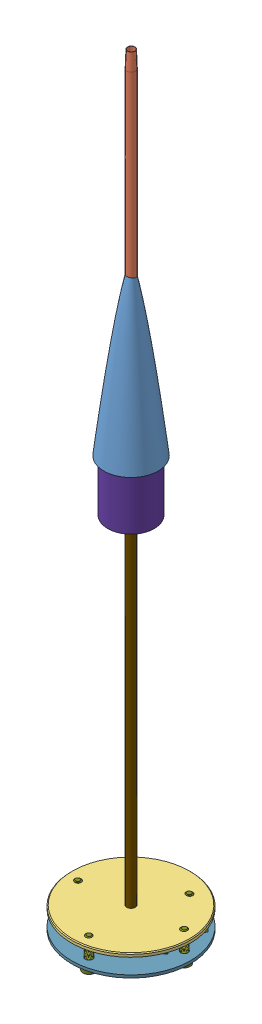
SolidWorks assembly NoseconeAsm, configuration Default. Lengths in mm.
Overall size (98.34 454.25 98.34).
84 component instances, 19 part files, 9 mates.
Components (placement in the parent):
- noseCone-1: noseCone [Default] at (226.7218 161.1206 645.7586) x (-1 0 0) z (0 0 1) size (120 813.97 120) (hidden)
- NOSECONE_TIP-1: NOSECONE_TIP [Default] at (226.717 961.2789 645.6249) x (0 -1 0) z (0.999354 0 -0.035938) size (105.75 31.88 31.88)
- PTube-1: PTube [Default] at (226.717 843.0906 645.6249) x (0.614963 0 0.788556) z (-0.788556 0 0.614963) size (5.11 225 5.11)
- PCB_retainer_Asm-1: PCB_retainer_Asm [Default] at (226.7218 629.513 645.7586) size (98.34 18.34 98.34)
  - Retaining plate-1: Retaining plate [Default] at origin size (70.03 2 70.03)
  - BansheePCB-1: BansheePCB [Default] at (49.813 -10.6 179.2168) x (-0.785717 0 -0.618586) z (0 1 0) size (70.03 70.03 10.55)
    - PT0.step-1: PT0.step [Default] at origin size (70.03 70.03 10.55)
      - PinHeader_2x05_P1.27mm_Vertical.step-1: PinHeader_2x05_P1.27mm_Vertical.step [Default] at (148.25 -130.23 -0.05) x (1 0 0) z (0 0 -1) size (3.4 6.35 6.3)
        - SOLID.step-1: SOLID.step [Default] at origin size (3.4 6.35 6.3)
      - SOT-23.step-1: SOT-23.step [Default] at (138 -129 1.65) size (2.5 3 1.2)
        - SOLID-0.step-1: SOLID-0.step [Default] at origin size (2.5 3 1.2)
      - SOT-23.step-2: SOT-23.step [Default] at (138 -124 1.65) size (2.5 3 1.2)
        - SOLID-0.step-1: SOLID-0.step [Default] at origin size (2.5 3 1.2)
      - R_0805_2012Metric.step-1: R_0805_2012Metric.step [Default] at (177.975 -120 1.65) size (2 1.2 0.45)
        - SOLID-1.step-1: SOLID-1.step [Default] at origin size (2 1.2 0.45)
      - R_0805_2012Metric.step-2: R_0805_2012Metric.step [Default] at (144 -95.975 1.65) x (0 1 0) z (0 0 1) size (2 1.2 0.45)
        - SOLID-1.step-1: SOLID-1.step [Default] at origin size (2 1.2 0.45)
      - R_0805_2012Metric.step-3: R_0805_2012Metric.step [Default] at (146 -96.025 1.65) x (0 1 0) z (0 0 1) size (2 1.2 0.45)
        - SOLID-1.step-1: SOLID-1.step [Default] at origin size (2 1.2 0.45)
      - JST_PH_S2B-PH-K_1x02_P2.00mm_Horizontal.step-1: JST_PH_S2B-PH-K_1x02_P2.00mm_Horizontal.step [Default] at (146 -140 1.65) x (-1 0 0) z (0 0 1) size (5.9 7.6 8.25)
        - SOLID-2.step-1: SOLID-2.step [Default] at origin size (5.9 7.6 8.25)
      - C_0603_1608Metric.step-1: C_0603_1608Metric.step [Default] at (163.7875 -114 1.65) size (1.6 0.8 0.8)
        - SOLID-3.step-1: SOLID-3.step [Default] at origin size (1.6 0.8 0.8)
      - C_0603_1608Metric.step-2: C_0603_1608Metric.step [Default] at (157 -117.7875 1.65) x (0 -1 0) z (0 0 1) size (1.6 0.8 0.8)
        - SOLID-3.step-1: SOLID-3.step [Default] at origin size (1.6 0.8 0.8)
      - QFN-24-1EP_4x4mm_P0.5mm_EP2.7x2.6mm.step-1: QFN-24-1EP_4x4mm_P0.5mm_EP2.7x2.6mm.step [Default] at (176.05 -112.25 1.65) size (4 4 1.1)
        - SOLID-4.step-1: SOLID-4.step [Default] at origin size (4 4 1.1)
      - Bosch_LGA-8_2x2.5mm_P0.65mm_ClockwisePinNumbering.step-1: Bosch_LGA-8_2x2.5mm_P0.65mm_ClockwisePinNumbering.step [Default] at (150 -110 1.65) size (2.5 2 0.78)
        - SOLID-5.step-1: SOLID-5.step [Default] at origin size (2.5 2 0.78)
      - LQFP-48_7x7mm_P0.5mm.step-1: LQFP-48_7x7mm_P0.5mm.step [Default] at (169 -127 1.65) x (0.707107 -0.707107 0) z (0 0 1) size (9 9 1.5)
        - SOLID-6.step-1: SOLID-6.step [Default] at origin size (9 9 1.5)
      - R_0805_2012Metric.step-4: R_0805_2012Metric.step [Default] at (155 -95.975 1.65) x (0 1 0) z (0 0 1) size (2 1.2 0.45)
        - SOLID-1.step-1: SOLID-1.step [Default] at origin size (2 1.2 0.45)
      - R_0805_2012Metric.step-5: R_0805_2012Metric.step [Default] at (142.975 -121 1.65) size (2 1.2 0.45)
        - SOLID-1.step-1: SOLID-1.step [Default] at origin size (2 1.2 0.45)
      - R_0805_2012Metric.step-6: R_0805_2012Metric.step [Default] at (129 -122 1.65) x (0 1 0) z (0 0 1) size (2 1.2 0.45)
        - SOLID-1.step-1: SOLID-1.step [Default] at origin size (2 1.2 0.45)
      - R_0805_2012Metric.step-7: R_0805_2012Metric.step [Default] at (164 -116.975 1.65) x (0 -1 0) z (0 0 1) size (2 1.2 0.45)
        - SOLID-1.step-1: SOLID-1.step [Default] at origin size (2 1.2 0.45)
      - R_0805_2012Metric.step-8: R_0805_2012Metric.step [Default] at (143 -119 1.65) size (2 1.2 0.45)
        - SOLID-1.step-1: SOLID-1.step [Default] at origin size (2 1.2 0.45)
      - R_0805_2012Metric.step-9: R_0805_2012Metric.step [Default] at (131 -121.975 1.65) x (0 1 0) z (0 0 1) size (2 1.2 0.45)
        - SOLID-1.step-1: SOLID-1.step [Default] at origin size (2 1.2 0.45)
      - LED_0805_2012Metric.step-1: LED_0805_2012Metric.step [Default] at (149.025 -121 -0.05) x (-1 0 0) z (0 0 -1) size (2 1.25 1.1)
        - SOLID-7.step-1: SOLID-7.step [Default] at origin size (2 1.25 1.1)
      - LED_0805_2012Metric.step-2: LED_0805_2012Metric.step [Default] at (149.025 -119 -0.05) x (-1 0 0) z (0 0 -1) size (2 1.25 1.1)
        - SOLID-7.step-1: SOLID-7.step [Default] at origin size (2 1.25 1.1)
      - C_0805_2012Metric.step-1: C_0805_2012Metric.step [Default] at (177.975 -118 1.65) x (-1 0 0) z (0 0 1) size (2 1.25 1.25)
        - SOLID-8.step-1: SOLID-8.step [Default] at origin size (2 1.25 1.25)
      - C_0805_2012Metric.step-2: C_0805_2012Metric.step [Default] at (177 -106 1.65) x (0 -1 0) z (0 0 1) size (2 1.25 1.25)
        - SOLID-8.step-1: SOLID-8.step [Default] at origin size (2 1.25 1.25)
      - C_0805_2012Metric.step-3: C_0805_2012Metric.step [Default] at (181 -111.975 1.65) x (0 -1 0) z (0 0 1) size (2 1.25 1.25)
        - SOLID-8.step-1: SOLID-8.step [Default] at origin size (2 1.25 1.25)
      - C_0805_2012Metric.step-4: C_0805_2012Metric.step [Default] at (173.025 -116 1.65) x (-1 0 0) z (0 0 1) size (2 1.25 1.25)
        - SOLID-8.step-1: SOLID-8.step [Default] at origin size (2 1.25 1.25)
      - C_0805_2012Metric.step-5: C_0805_2012Metric.step [Default] at (139 -109.975 1.65) x (0 -1 0) z (0 0 1) size (2 1.25 1.25)
        - SOLID-8.step-1: SOLID-8.step [Default] at origin size (2 1.25 1.25)
      - C_0805_2012Metric.step-6: C_0805_2012Metric.step [Default] at (161.975 -81 1.65) size (2 1.25 1.25)
        - SOLID-8.step-1: SOLID-8.step [Default] at origin size (2 1.25 1.25)
      - C_0805_2012Metric.step-7: C_0805_2012Metric.step [Default] at (139 -114 1.65) x (0 -1 0) z (0 0 1) size (2 1.25 1.25)
        - SOLID-8.step-1: SOLID-8.step [Default] at origin size (2 1.25 1.25)
      - C_0805_2012Metric.step-8: C_0805_2012Metric.step [Default] at (161.025 -121 1.65) x (-1 0 0) z (0 0 1) size (2 1.25 1.25)
        - SOLID-8.step-1: SOLID-8.step [Default] at origin size (2 1.25 1.25)
      - C_0805_2012Metric.step-9: C_0805_2012Metric.step [Default] at (161 -123 1.65) x (-1 0 0) z (0 0 1) size (2 1.25 1.25)
        - SOLID-8.step-1: SOLID-8.step [Default] at origin size (2 1.25 1.25)
      - C_0805_2012Metric.step-10: C_0805_2012Metric.step [Default] at (171 -119.025 1.65) x (0 1 0) z (0 0 1) size (2 1.25 1.25)
        - SOLID-8.step-1: SOLID-8.step [Default] at origin size (2 1.25 1.25)
      - C_0805_2012Metric.step-11: C_0805_2012Metric.step [Default] at (176 -129.025 1.65) x (-0.707107 -0.707107 0) z (0 0 1) size (2 1.25 1.25)
        - SOLID-8.step-1: SOLID-8.step [Default] at origin size (2 1.25 1.25)
      - C_0805_2012Metric.step-12: C_0805_2012Metric.step [Default] at (168 -119.025 1.65) x (0 1 0) z (0 0 1) size (2 1.25 1.25)
        - SOLID-8.step-1: SOLID-8.step [Default] at origin size (2 1.25 1.25)
      - C_0805_2012Metric.step-13: C_0805_2012Metric.step [Default] at (169 -135.025 1.65) x (0 -1 0) z (0 0 1) size (2 1.25 1.25)
        - SOLID-8.step-1: SOLID-8.step [Default] at origin size (2 1.25 1.25)
      - COMPOUND.step-1: COMPOUND.step [Default] at origin size (70.03 70.03 1.6)
  - 90965A150_TYPE 316 STAINLESS STEEL FLAT WASHER-1: 90965A150_TYPE 316 STAINLESS STEEL FLAT WASHER [90965A150] at (-28.0861 -11.5 3.3426) x (-0.85321 0 -0.521568) z (0 1 0) size (9 9 0.9)
  - 91290A150_BLACK-OXIDE CLASS 12.9 SOCKET HEAD CAP SCREW-1: 91290A150_BLACK-OXIDE CLASS 12.9 SOCKET HEAD CAP SCREW [91290A150] at (-28.0861 2.5 3.3426) x (-0.837169 0 -0.546944) z (0 1 0) size (7 7 18.34)
  - 90965A150_TYPE 316 STAINLESS STEEL FLAT WASHER-2: 90965A150_TYPE 316 STAINLESS STEEL FLAT WASHER [90965A150] at (3.3426 -10.6 28.0861) x (1 0 0) z (0 -1 0) size (9 9 0.9)
  - 91290A150_BLACK-OXIDE CLASS 12.9 SOCKET HEAD CAP SCREW-2: 91290A150_BLACK-OXIDE CLASS 12.9 SOCKET HEAD CAP SCREW [91290A150] at (3.3426 2.5 28.0861) x (0.792794 0 0.60949) z (0 1 0) size (7 7 18.34)
  - 90965A150_TYPE 316 STAINLESS STEEL FLAT WASHER-3: 90965A150_TYPE 316 STAINLESS STEEL FLAT WASHER [90965A150] at (28.0861 -11.5 -3.3426) x (1 0 0) z (0 1 0) size (9 9 0.9)
  - 91290A150_BLACK-OXIDE CLASS 12.9 SOCKET HEAD CAP SCREW-3: 91290A150_BLACK-OXIDE CLASS 12.9 SOCKET HEAD CAP SCREW [91290A150] at (28.0861 2.5 -3.3426) x (0.998932 0 0.046194) z (0 1 0) size (7 7 18.34)
  - 90965A150_TYPE 316 STAINLESS STEEL FLAT WASHER-4: 90965A150_TYPE 316 STAINLESS STEEL FLAT WASHER [90965A150] at (11.5361 -11.5 -22.7359) x (-0.837169 0 -0.546944) z (0 1 0) size (9 9 0.9)
  - 91290A150_BLACK-OXIDE CLASS 12.9 SOCKET HEAD CAP SCREW-4: 91290A150_BLACK-OXIDE CLASS 12.9 SOCKET HEAD CAP SCREW [91290A150] at (11.5361 2.5 -22.7359) x (-0.974335 0 0.225102) z (0 1 0) size (7 7 18.34)
- sensorMount-1: sensorMount [Default] at (226.7218 830.3106 645.7586) size (27.43 30.48 27.43)
- Rod-1: Rod [Default] at (226.7218 621.3906 645.7586) size (5.11 214 5.11)
Mates (geometry in assembly coordinates):
- Concentric1: concentric aligned: cone of noseCone-1 through (226.7218 860.7906 645.7586) axis (0 1 0); circle of NOSECONE_TIP-1
- Coincident4: coincident anti-aligned: plane of noseCone-1 through (239.8862 860.7906 645.7586) normal (0 1 0); plane of NOSECONE_TIP-1 through (226.717 860.7906 645.6249) normal (0 -1 0)
- Concentric2: concentric aligned: cylinder of NOSECONE_TIP-1 through (226.717 848.0906 645.6249) axis (0 -1 0) radius 2.5527; cylinder of PTube-1 through (226.717 1068.0906 645.6249) axis (0 -1 0) radius 2.555
- Distance1: distance = 5 mm aligned: plane of PTube-1 through (226.717 843.0906 645.6249) normal (0 -1 0); plane of NOSECONE_TIP-1 through (226.717 848.0906 645.6249) normal (0 -1 0)
- Concentric4: concentric anti-aligned: cylinder of noseCone-1 through (226.7218 950.5678 645.7586) axis (0 1 0) radius 54.06; cylinder of PCB_retainer_Asm-1/Retaining plate-1 through (226.7218 631.513 645.7586) axis (0 -1 0) radius 35.015
- Coincident7: coincident anti-aligned: plane of NOSECONE_TIP-1 through (226.717 860.7906 645.6249) normal (0 -1 0); plane of sensorMount-1 through (226.7218 860.7906 645.7586) normal (0 1 0)
- Concentric5: concentric aligned: circle of NOSECONE_TIP-1; circle of sensorMount-1
- Coincident9: coincident aligned: circle of sensorMount-1; plane of Rod-1 through (226.7218 835.3906 645.7586) normal (0 1 0)
- Concentric6: concentric aligned: circle of sensorMount-1; circle of Rod-1
